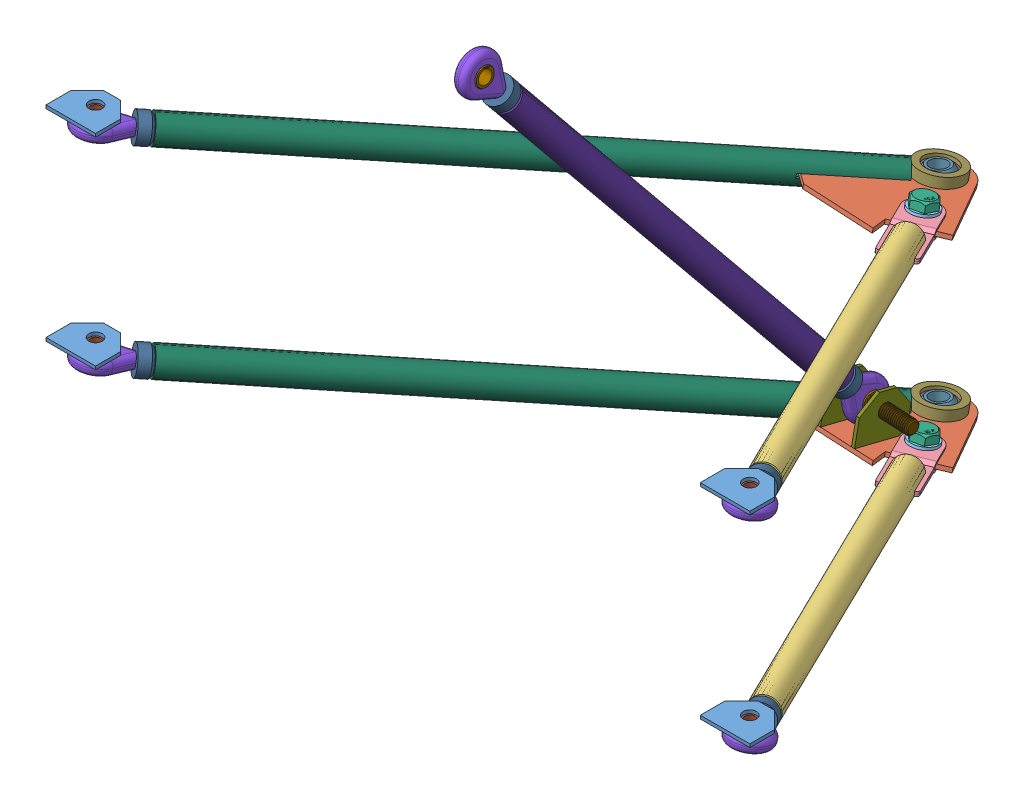
SolidWorks assembly Control Arms, Pushord, Bellcrank, configuration Default. Lengths in mm.
Overall size (449.35 328.95 365.63).
64 component instances, 19 part files, 22 mates.
Components (placement in the parent):
- frame connectors-10: frame connectors [Default] at (-357.6393 7.7366 39.1204) size (30 2 25)
- frame connectors-11: frame connectors [Default] at (38.6473 7.7366 39.1204) size (30 2 25)
- Upper Control Arm Assembly-1: Upper Control Arm Assembly [Default] at (-132.0035 -180.9798 -245.6486) x (0.997989 0.012488 0.062153) z (-0.063395 0.196589 0.978434) size (428.79 42.68 337.86) (flexible)
  - Front Control Arm Plate-1: Front Control Arm Plate [Default] at origin size (91 2.5 76.52)
  - Rear Upper Control Arm-2: Rear Upper Control Arm [Default] at (105.6055 0 154.4308) x (-0.554844 0 -0.831954) z (0.831954 0 -0.554844) size (250 16 16)
  - Control Arm Link Plate-1: Control Arm Link Plate [Default] at (31.8652 1.25 43.6848) x (-0.554844 0 -0.831954) z (0.831954 0 -0.554844) size (54.1 2.5 20)
  - Control Arm Link Plate-2: Control Arm Link Plate [Default] at (31.8652 -1.25 43.6848) x (-0.554844 0 -0.831954) z (-0.831954 0 0.554844) size (54.1 2.5 20)
  - plain washer normal grade a_iso-1: plain washer normal grade a_iso [Washer ISO 7089 - 8] at (22.4051 2.5 29.5) x (0 -1 0) z (0.774417 0 0.632675) size (1.6 16 16)
  - 94863A205_High-Strength Class 10.9 Steel Hex Head Screw-1: 94863A205_High-Strength Class 10.9 Steel Hex Head Screw [94863A205] at (22.4051 4.1 29.5) x (0.632675 0 -0.774417) z (0 1 0) size (13 16.35 25.89)
  - 94645A111_High-Strength Steel Nylon-Insert Locknut-1: 94645A111_High-Strength Steel Nylon-Insert Locknut [94645A111] at (22.4051 -6.5 29.5) x (-0.775761 0 -0.631027) z (-0.631027 0 0.775761) size (13 8 14.93)
  - Link Insert Assembly-1: Link Insert Assembly [Default] at (151.1806 41.9532 246.62) x (0.831954 0 -0.554844) z (0 -1 0) size (24 54 13.75) (flexible)
    - Link-1: Link [Default] at (13.2343 18.3157 41.9532) size (24 54 13.75)
    - Spherical Bearing Ball-1: Spherical Bearing Ball [Default] at (13.2343 47.8157 41.9532) x (0.098687 -0.170482 0.980406) z (0.465638 -0.862793 -0.196901) size (9 13.75 13.75)
  - Control Arm Insert-1: Control Arm Insert [Default] at (162.0573 0 239.0767) x (-0.831525 0.032128 0.554558) z (0.026729 0.999484 -0.017826) size (16 25 16)
  - 8mm Spehrical Bearing Insert-1: 8mm Spehrical Bearing Insert [Default] at (188.8024 6.3726 280.3354) x (0.943598 0.053499 -0.326741) z (-0.330856 0.189582 -0.924442) size (11 9 11)
  - Spherical Bearing Seat-1: Spherical Bearing Seat [Default] at (0 -0.3 0) size (30 15.1 30)
  - Wide Spherical Bearing-1: Wide Spherical Bearing [Default] at (-7.3247 -16.3877 13.3464) x (1 0 0) z (0 1 0) size (27.49 27.93 16.36) (flexible)
    - Wide Bearing Cage-1: Wide Bearing Cage [Default] at (7.3247 13.3464 16.0877) size (22 22 10.5)
    - Wide Ball-1: Wide Ball [Default] at (7.3247 13.3464 16.0877) x (-0.805196 0.592973 0.006499) z (-0.067634 -0.102717 0.992409) size (19.04 19.04 14)
  - Front Upper Control Arm-1: Front Upper Control Arm [Default] at (-100.6334 0 146.8287) x (0.559193 0 -0.829038) z (0.829038 0 0.559193) size (330 16 16)
  - Link Insert Assembly-2: Link Insert Assembly [Default] at (-191.0018 41.9532 257.1385) x (0.829038 0 0.559193) z (0 -1 0) size (24 54 13.75) (flexible)
    - Link-1: Link [Default] at (13.2343 18.3157 41.9532) size (24 54 13.75)
    - Spherical Bearing Ball-1: Spherical Bearing Ball [Default] at (13.2343 47.8157 41.9532) x (-0.120284 -0.155997 0.980406) z (-0.674993 -0.711316 -0.195994) size (9 13.75 13.75)
  - Control Arm Insert-2: Control Arm Insert [Default] at (-179.8953 0 264.3393) x (-0.82861 0.032128 -0.558904) z (0.026635 0.999484 0.017966) size (16 25 16)
  - 8mm Spehrical Bearing Insert-2: 8mm Spehrical Bearing Insert [Default] at (-206.6871 6.3726 305.4578) x (-0.995357 0.030953 -0.091139) z (-0.095438 -0.194538 0.976241) size (11 9 11)
  - Push Rod Upper Control Arm Bracket-1: Push Rod Upper Control Arm Bracket [Default] at (10.7762 13.75 44.5) x (0 0 1) z (0 -1 0) size (30 2 25)
  - Push Rod Upper Control Arm Bracket-2: Push Rod Upper Control Arm Bracket [Default] at (-11.2238 13.75 44.5) x (0 0 1) z (0 -1 0) size (30 2 25)
- frame connectors-14: frame connectors [Default] at (-357.6393 -114.2634 39.1204) size (30 2 25)
- frame connectors-15: frame connectors [Default] at (38.6473 -114.2634 39.1204) size (30 2 25)
- Lower Control Arm Assembly-4: Lower Control Arm Assembly [Default] at (-132.0035 -58.9798 -245.6486) x (0.997989 0.012488 0.062153) z (-0.063395 0.196589 0.978434) size (428.79 26.25 337.86) (flexible)
  - Front Control Arm Plate-1: Front Control Arm Plate [Default] at origin size (91 2.5 76.52)
  - Rear Upper Control Arm-2: Rear Upper Control Arm [Default] at (105.6055 0 154.4308) x (-0.554844 0 -0.831954) z (0.831954 0 -0.554844) size (250 16 16)
  - Control Arm Link Plate-1: Control Arm Link Plate [Default] at (31.8652 1.25 43.6848) x (-0.554844 0 -0.831954) z (0.831954 0 -0.554844) size (54.1 2.5 20)
  - Control Arm Link Plate-2: Control Arm Link Plate [Default] at (31.8652 -1.25 43.6848) x (-0.554844 0 -0.831954) z (-0.831954 0 0.554844) size (54.1 2.5 20)
  - plain washer normal grade a_iso-1: plain washer normal grade a_iso [Washer ISO 7089 - 8] at (22.4051 2.5 29.5) x (0 -1 0) z (0.774417 0 0.632675) size (1.6 16 16)
  - 94863A205_High-Strength Class 10.9 Steel Hex Head Screw-1: 94863A205_High-Strength Class 10.9 Steel Hex Head Screw [94863A205] at (22.4051 4.1 29.5) x (0.632675 0 -0.774417) z (0 1 0) size (13 16.35 25.89)
  - 94645A111_High-Strength Steel Nylon-Insert Locknut-1: 94645A111_High-Strength Steel Nylon-Insert Locknut [94645A111] at (22.4051 -6.5 29.5) x (-0.783807 0 -0.621005) z (-0.621005 0 0.783807) size (13 8 14.93)
  - Link Insert Assembly-1: Link Insert Assembly [Default] at (151.1806 41.9532 246.62) x (0.831954 0 -0.554844) z (0 -1 0) size (24 54 13.75) (flexible)
    - Link-1: Link [Default] at (13.2343 18.3157 41.9532) size (24 54 13.75)
    - Spherical Bearing Ball-1: Spherical Bearing Ball [Default] at (13.2343 47.8157 41.9532) x (0.098687 -0.170482 0.980406) z (-0.213821 0.958571 0.188208) size (9 13.75 13.75)
  - Control Arm Insert-1: Control Arm Insert [Default] at (162.0573 0 239.0767) x (-0.831525 0.032128 0.554558) z (0.026729 0.999484 -0.017826) size (16 25 16)
  - 8mm Spehrical Bearing Insert-1: 8mm Spehrical Bearing Insert [Default] at (188.8024 6.3726 280.3354) x (0.570798 -0.168414 0.803633) z (0.820995 0.102177 -0.561717) size (11 9 11)
  - Spherical Bearing Seat-1: Spherical Bearing Seat [Default] at (0 -0.3 0) size (30 15.1 30)
  - Wide Spherical Bearing-1: Wide Spherical Bearing [Default] at (-7.3247 -16.3877 13.3464) x (1 0 0) z (0 1 0) size (27.09 27.54 16.29) (flexible)
    - Wide Bearing Cage-1: Wide Bearing Cage [Default] at (7.3247 13.3464 16.0877) size (22 22 10.5)
    - Wide Ball-1: Wide Ball [Default] at (7.3247 13.3464 16.0877) x (-0.848922 0.528509 -0.003153) z (-0.067634 -0.102717 0.992409) size (19.04 19.04 14)
  - Front Upper Control Arm-1: Front Upper Control Arm [Default] at (-100.6334 0 146.8287) x (0.559193 0 -0.829038) z (0.829038 0 0.559193) size (330 16 16)
  - Link Insert Assembly-2: Link Insert Assembly [Default] at (-191.0018 41.9532 257.1385) x (0.829038 0 0.559193) z (0 -1 0) size (24 54 13.75) (flexible)
    - Link-1: Link [Default] at (13.2343 18.3157 41.9532) size (24 54 13.75)
    - Spherical Bearing Ball-1: Spherical Bearing Ball [Default] at (13.2343 47.8157 41.9532) x (-0.120284 -0.155997 0.980406) z (-0.735276 -0.64954 -0.193561) size (9 13.75 13.75)
  - Control Arm Insert-2: Control Arm Insert [Default] at (-179.8953 0 264.3393) x (-0.82861 0.032128 -0.558904) z (0.026635 0.999484 0.017966) size (16 25 16)
  - 8mm Spehrical Bearing Insert-2: 8mm Spehrical Bearing Insert [Default] at (-206.6871 6.3726 305.4578) x (-0.997103 0.026963 -0.071128) z (-0.075035 -0.195131 0.977903) size (11 9 11)
- Front Push Rod Assembly-1: Front Push Rod Assembly [Default] at (-358.2946 -68.7631 97.7914) x (0.068489 -0.779206 -0.623015) z (0.997646 0.05555 0.040195) size (363.6 24 20.9) (flexible)
  - Front Push Rod-1: Front Push Rod [Default] at (102.5362 181.4229 205.1752) size (290 16 16)
  - Control Arm Insert-1: Control Arm Insert [Default] at (224.2796 181.4229 205.1752) x (0 -1 0) z (0 0 1) size (16 25 16)
  - Control Arm Insert-2: Control Arm Insert [Default] at (-19.2072 181.4229 205.1752) x (0 -0.381849 0.924225) z (0 -0.924225 -0.381849) size (16 25 16)
  - Link Insert Assembly-1: Link Insert Assembly [Default] at (-19.4481 168.1886 163.222) x (0 1 0) z (0 0 1) size (24 54 13.75)
    - Link-1: Link [Default] at (13.2343 18.3157 41.9532) size (24 54 13.75)
    - Spherical Bearing Ball-1: Spherical Bearing Ball [Default] at (13.2343 47.8157 41.9532) x (0 0 1) z (-0.821758 0.569836 0) size (9 13.75 13.75)
  - Link Insert Assembly-2: Link Insert Assembly [Default] at (224.5204 194.6572 163.222) x (0 -1 0) z (0 0 1) size (24 54 13.75) (flexible)
    - Link-1: Link [Default] at (13.2343 18.3157 41.9532) size (24 54 13.75)
    - Spherical Bearing Ball-1: Spherical Bearing Ball [Default] at (13.2343 47.8157 41.9532) x (0.044037 0.019898 0.998832) z (0.933329 -0.357405 -0.034029) size (9 13.75 13.75)
- M8 45mm hex bolt-1: M8 45mm hex bolt [91310A132] at (-130.038 -156.2401 -205.0112) x (0.041128 -0.873617 -0.484873) z (-0.997989 -0.012488 -0.062153) size (13 14.81 50.91)
- flat washer narrow_am-1: flat washer narrow_am [B18.22M - Plain washer, 8 mm, narrow] at (-147.0238 -156.4527 -206.069) x (0.997989 0.012488 0.062153) z (-0.063355 0.161874 0.984776) size (2.3 18.8 18.8)
Mates (geometry in assembly coordinates):
- Concentric18: concentric aligned: cylinder of frame connectors-10 through (-357.6393 8.7366 39.1204) axis (0 -1 0) radius 4; cylinder of frame connectors-14 through (-357.6393 -113.2634 39.1204) axis (0 -1 0) radius 4
- Coincident27: coincident aligned: plane of frame connectors-10 through (-372.6393 8.7366 54.1204) normal (0 0 1); plane of frame connectors-14 through (-372.6393 -113.2634 54.1204) normal (0 0 1)
- Distance2: distance = 120 mm anti-aligned: plane of frame connectors-14 through (-357.6393 -113.2634 39.1204) normal (0 1 0); plane of frame connectors-10 through (-357.6393 6.7366 39.1204) normal (0 -1 0)
- Concentric19: concentric aligned: cylinder of Upper Control Arm Assembly-1/8mm Spehrical Bearing Insert-2 through (-357.6393 -117.2634 39.1204) axis (0 -1 0) radius 3; cylinder of frame connectors-14 through (-357.6393 -113.2634 39.1204) axis (0 -1 0) radius 4
- Coincident29: coincident anti-aligned: plane of Upper Control Arm Assembly-1/8mm Spehrical Bearing Insert-2 through (-352.2076 -115.2634 39.9847) normal (0 1 0); plane of frame connectors-14 through (-357.6393 -115.2634 39.1204) normal (0 -1 0)
- Coincident30: coincident aligned: plane of frame connectors-14 through (-372.6393 -113.2634 54.1204) normal (0 0 1); plane of frame connectors-15 through (23.6473 -113.2634 54.1204) normal (0 0 1)
- Coincident31: coincident aligned: plane of frame connectors-14 through (-357.6393 -113.2634 39.1204) normal (0 1 0); plane of frame connectors-15 through (38.6473 -113.2634 39.1204) normal (0 1 0)
- Concentric21: concentric aligned: cylinder of frame connectors-10 through (-357.6393 8.7366 39.1204) axis (0 -1 0) radius 4; circle of Lower Control Arm Assembly-4/8mm Spehrical Bearing Insert-2
- Coincident33: coincident anti-aligned: plane of frame connectors-10 through (-357.6393 6.7366 39.1204) normal (0 -1 0); plane of Lower Control Arm Assembly-4/8mm Spehrical Bearing Insert-2 through (-352.191 6.7366 39.8732) normal (0 1 0)
- Coincident38: coincident anti-aligned: plane of Upper Control Arm Assembly-1/8mm Spehrical Bearing Insert-1 through (33.354 -115.2634 40.6141) normal (0 1 0); plane of frame connectors-15 through (38.6473 -115.2634 39.1204) normal (0 -1 0)
- Concentric22: concentric aligned: cylinder of Upper Control Arm Assembly-1/8mm Spehrical Bearing Insert-1 through (38.6473 -117.2634 39.1204) axis (0 -1 0) radius 3; cylinder of frame connectors-15 through (38.6473 -113.2634 39.1204) axis (0 -1 0) radius 4
- Coincident39: coincident aligned: plane of frame connectors-10 through (-372.6393 8.7366 54.1204) normal (0 0 1); plane of frame connectors-11 through (23.6473 8.7366 54.1204) normal (0 0 1)
- Coincident40: coincident aligned: plane of frame connectors-10 through (-357.6393 8.7366 39.1204) normal (0 1 0); plane of frame connectors-11 through (38.6473 8.7366 39.1204) normal (0 1 0)
- Concentric23: concentric aligned: cylinder of frame connectors-11 through (38.6473 8.7366 39.1204) axis (0 -1 0) radius 4; cylinder of Lower Control Arm Assembly-4/8mm Spehrical Bearing Insert-1 through (38.6473 4.7366 39.1204) axis (0 -1 0) radius 3
- Coincident41: coincident anti-aligned: plane of frame connectors-11 through (38.6473 6.7366 39.1204) normal (0 -1 0); plane of Lower Control Arm Assembly-4/8mm Spehrical Bearing Insert-1 through (35.7944 6.7366 34.4182) normal (0 1 0)
- Parallel9: parallel aligned: plane of Upper Control Arm Assembly-1/Front Control Arm Plate-1 through (-132.0025 -179.7576 -245.911) normal (0 0.980406 -0.196986); plane of Lower Control Arm Assembly-4/Front Control Arm Plate-1 through (-132.0025 -57.7576 -245.911) normal (0 0.980406 -0.196986)
- Concentric24: concentric anti-aligned: cylinder of Upper Control Arm Assembly-1/Push Rod Upper Control Arm Bracket-2 through (-147.0238 -156.4527 -206.069) axis (0.997989 0.012488 0.062153) radius 4; cylinder of flat washer narrow_am-1 through (-181.8786 -156.8888 -208.2397) axis (-0.997989 -0.012488 -0.062153) radius 4.56
- Coincident42: coincident anti-aligned: plane of Upper Control Arm Assembly-1/Push Rod Upper Control Arm Bracket-2 through (-147.0238 -158.9037 -205.5765) normal (-0.997989 -0.012488 -0.062153); plane of flat washer narrow_am-1 through (-147.034 -151.9532 -206.8093) normal (0.997989 0.012488 0.062153)
- Concentric25: concentric anti-aligned: cylinder of Upper Control Arm Assembly-1/Push Rod Upper Control Arm Bracket-2 through (-147.0238 -156.4527 -206.069) axis (0.997989 0.012488 0.062153) radius 4; cylinder of M8 45mm hex bolt-1 through (-149.8481 -156.488 -206.2449) axis (-0.997989 -0.012488 -0.062153) radius 5.7528
- Coincident43: coincident anti-aligned: plane of M8 45mm hex bolt-1 through (-149.3192 -156.4814 -206.212) normal (0.997989 0.012488 0.062153); plane of flat washer narrow_am-1 through (-149.3402 -147.2061 -207.738) normal (-0.997989 -0.012488 -0.062153)
- Concentric26: concentric aligned: cylinder of Front Push Rod Assembly-1/Link Insert Assembly-2/Spherical Bearing Ball-1 through (-142.4099 -156.3949 -205.7817) axis (-0.997989 -0.012488 -0.062153) radius 4; cylinder of M8 45mm hex bolt-1 through (-149.8481 -156.488 -206.2449) axis (-0.997989 -0.012488 -0.062153) radius 5.7528
- Distance3: distance = 6 mm anti-aligned: plane of Front Push Rod Assembly-1/Link Insert Assembly-2/Spherical Bearing Ball-1 through (-131.2166 -151.3028 -203.4898) normal (0.997989 0.012488 0.062153); plane of Upper Control Arm Assembly-1/Push Rod Upper Control Arm Bracket-1 through (-125.0681 -158.6289 -204.2092) normal (-0.997989 -0.012488 -0.062153)
